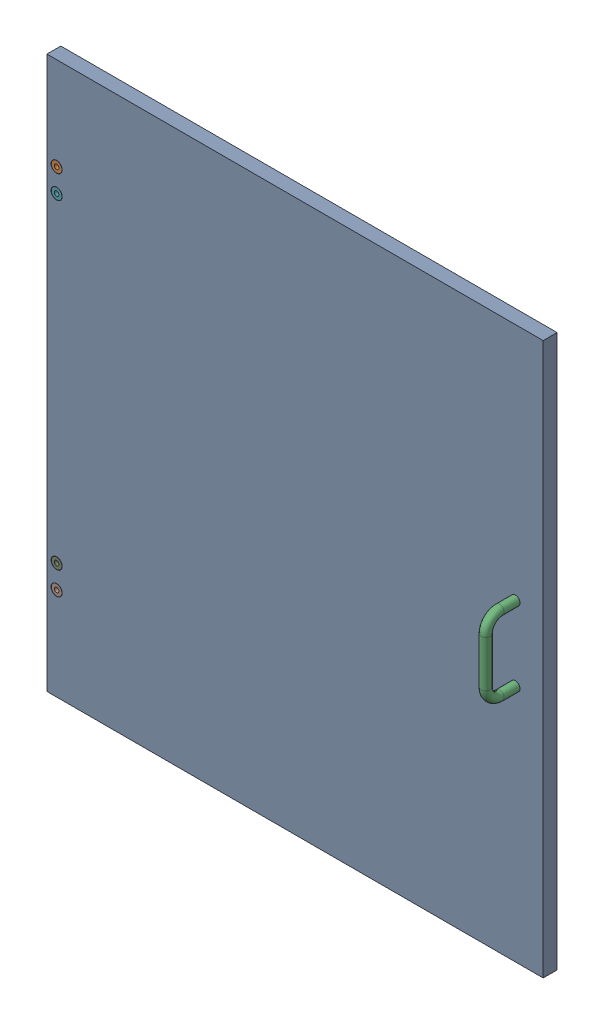
SolidWorks assembly s-assy-leftlarge, configuration ﾃﾞﾌｫﾙﾄ. Lengths in mm.
Overall size (535 595 53).
12 component instances, 5 part files, 12 mates.
Components (placement in the parent):
- plate_left_large-1: plate_left_large [ﾃﾞﾌｫﾙﾄ] at origin size (535 595 15)
- Onimenut_m5-1: Onimenut_m5 [ﾃﾞﾌｫﾙﾄ] at (-257 197.5 2) x (0 0 -1) z (-0.034635 -0.9994 0) size (13 11.5 11.5)
- MISUMI_C-NUWANS10-80-27-1: MISUMI_C-NUWANS10-80-27 [Default] at (237.5 0 15) x (0 -1 0) z (-1 0 0) size (90 37 10)
- Onimenut_m3-1: Onimenut_m3 [ﾃﾞﾌｫﾙﾄ] at (260 188.5 0) x (0.9303 -0.3668 0) z (0 0 1) size (4 4 8.5)
- MISUMI_E-GCBSTSR5-20-1: MISUMI_E-GCBSTSR5-20 [Default] at (237.5 40 0) x (0 0 1) z (-1 0 0) size (21 9 9)
- MISUMI_E-GCBSTSR5-20-2: MISUMI_E-GCBSTSR5-20 [Default] at (237.5 -40 0) x (0 0 1) z (-1 0 0) size (21 9 9)
- Onimenut_m5-2: Onimenut_m5 [ﾃﾞﾌｫﾙﾄ] at (-257 172.5 2) x (0 0 -1) z (-0.034635 -0.9994 0) size (13 11.5 11.5)
- Onimenut_m5-3: Onimenut_m5 [ﾃﾞﾌｫﾙﾄ] at (-257 -197.5 2) x (0 0 -1) z (0.034635 -0.9994 0) size (13 11.5 11.5)
- Onimenut_m5-4: Onimenut_m5 [ﾃﾞﾌｫﾙﾄ] at (-257 -172.5 2) x (0 0 -1) z (0.034635 -0.9994 0) size (13 11.5 11.5)
- Onimenut_m3-2: Onimenut_m3 [ﾃﾞﾌｫﾙﾄ] at (260 176.5 0) x (0.9303 -0.3668 0) z (0 0 1) size (4 4 8.5)
- Onimenut_m3-3: Onimenut_m3 [ﾃﾞﾌｫﾙﾄ] at (260 -188.5 8.5) x (0.9303 0.3668 0) z (0 0 -1) size (4 4 8.5)
- Onimenut_m3-4: Onimenut_m3 [ﾃﾞﾌｫﾙﾄ] at (260 -176.5 8.5) x (0.9303 0.3668 0) z (0 0 -1) size (4 4 8.5)
Mates (geometry in assembly coordinates):
- 一致1: coordinate: point of plate_left_large-1
- 同心円1: concentric anti-aligned: cylinder of plate_left_large-1 through (-257 197.5 0) axis (0 0 1) radius 4; cylinder of Onimenut_m5-1 through (-257 197.5 2) axis (0 0 -1) radius 5.5
- 一致2: coincident anti-aligned: plane of plate_left_large-1 through (-257 197.5 14) normal (0 0 1); plane of Onimenut_m5-1 through (-257 197.5 14) normal (0 0 -1)
- 同心円2: concentric anti-aligned: cylinder of plate_left_large-1 through (237.5 -40 0) axis (0 0 1) radius 2.5; cylinder of MISUMI_C-NUWANS10-80-27-1 through (237.5 -40 32) axis (0 0 -1) radius 5
- 同心円3: concentric anti-aligned: cylinder of plate_left_large-1 through (237.5 40 0) axis (0 0 1) radius 2.5; cylinder of MISUMI_C-NUWANS10-80-27-1 through (237.5 40 32) axis (0 0 -1) radius 5
- 一致3: coincident anti-aligned: plane of plate_left_large-1 through (0 0 15) normal (0 0 1); plane of MISUMI_C-NUWANS10-80-27-1 through (237.5 40 15) normal (0 0 -1)
- 同心円4: concentric aligned: cylinder of plate_left_large-1 through (260 188.5 9) axis (0 0 -1) radius 2; cylinder of Onimenut_m3-1 through (260 188.5 8.5) axis (0 0 -1) radius 2
- 一致4: coincident anti-aligned: plane of plate_left_large-1 through (0 0 0) normal (0 0 -1); circle of Onimenut_m3-1
- 同心円5: concentric anti-aligned: cylinder of plate_left_large-1 through (237.5 40 0) axis (0 0 1) radius 2.5; cylinder of MISUMI_E-GCBSTSR5-20-1 through (237.5 40 -1) axis (0 0 -1) radius 2.5
- 一致5: coincident aligned: plane of plate_left_large-1 through (0 0 0) normal (0 0 -1); circle of MISUMI_E-GCBSTSR5-20-1
- 同心円6: concentric anti-aligned: cylinder of plate_left_large-1 through (237.5 -40 0) axis (0 0 1) radius 2.5; cylinder of MISUMI_E-GCBSTSR5-20-2 through (237.5 -40 -1) axis (0 0 -1) radius 2.5
- 一致6: coincident anti-aligned: plane of plate_left_large-1 through (0 0 0) normal (0 0 -1); plane of MISUMI_E-GCBSTSR5-20-2 through (237.5 -37.745 0) normal (0 0 1)
